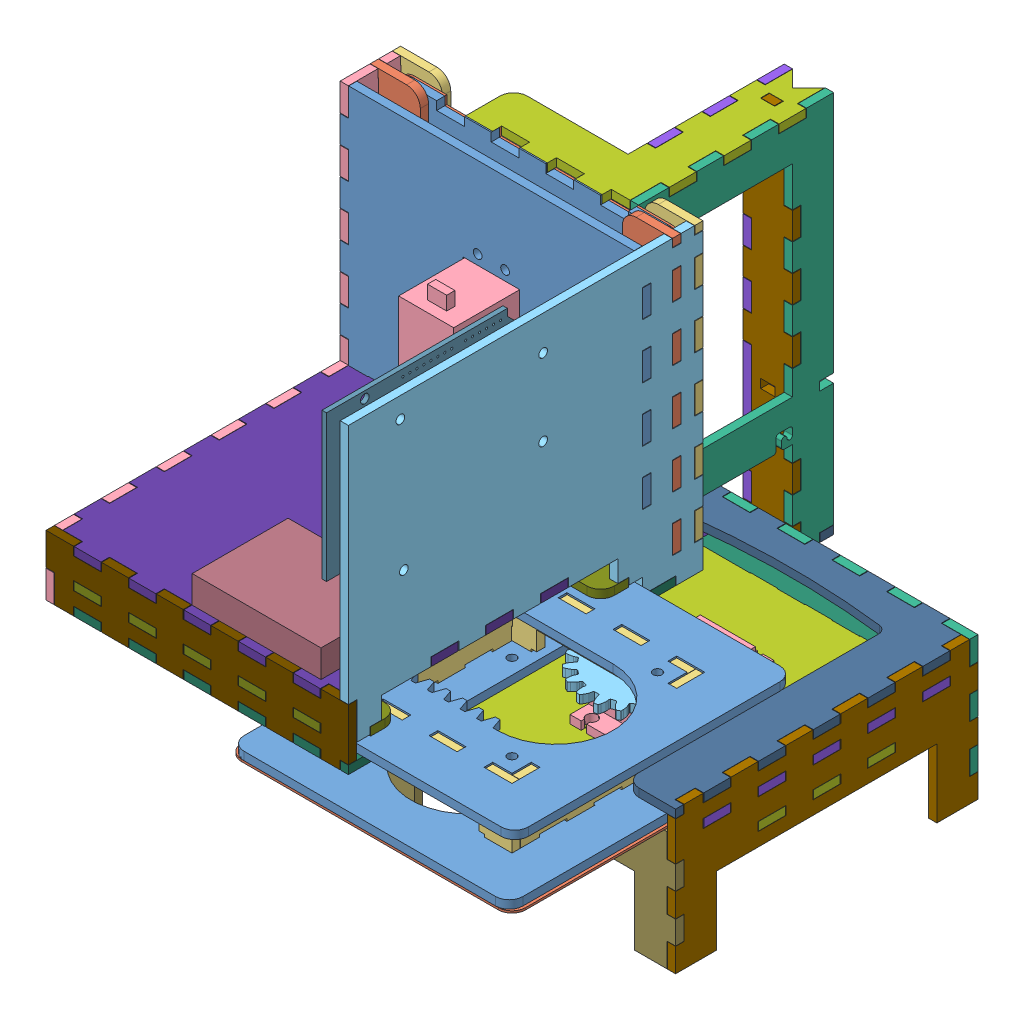
SolidWorks assembly biccolo, configuration Default. Lengths in mm.
Overall size (170.04 173.29 197.34).
41 component instances, 29 part files, 143 mates.
Components (placement in the parent):
- biccolo_rack_panel0-1: biccolo_rack_panel0 [zrack] at (0 0 186.843) size (101.74 3 103.74) (hidden)
- biccolo_rack_panel0-2: biccolo_rack_panel0 [Default] at (0 45 186.843) size (101.74 3 103.74)
- biccolo_rack_panel0-3: biccolo_rack_panel0 [Default] at (11.9708 70 174.8722) x (0 0 1) z (1 0 0) size (101.74 3 103.74)
- biccolo_rack_bearing-1: biccolo_rack_bearing [blank] at (0 45 186.843) size (103.74 0.75 103.74)
- biccolo_rack_panel1-1: biccolo_rack_panel1 [Default] at (0 45 139.8138) x (-1 0 0) z (0 -1 0) size (70.12 3 24)
- biccolo_rack_panel1-2: biccolo_rack_panel1 [Default] at (32.0585 70 174.8722) x (0 0 -1) z (0 1 0) size (70.12 3 24)
- biccolo_rack_panel1-3: biccolo_rack_panel1 [Default] at (0 45 209.9307) x (1 0 0) z (0 -1 0) size (70.12 3 24)
- biccolo_rack_panel1-4: biccolo_rack_panel1 [Default] at (-32.0585 70 174.8722) x (0 0 1) z (0 1 0) size (70.12 3 24)
- fs5106b-1: fs5106b [Default] at (0 6.2 126.843) x (0 0 1) z (-1 0 0) size (54.3 42.8 20.1)
- biccolo_6mm_gear-1: biccolo_6mm_gear [Default] at (19.0986 45 126.843) x (-1 0 0) z (0 1 0) size (41.67 41.67 3)
- biccolo_stage0_panel5-1: biccolo_stage0_panel5 [Default] at (0 0 60) x (1 0 0) z (0 -1 0) size (110.34 3 52.05)
- biccolo_stage0_panel0-1: biccolo_stage0_panel0 [Default] at (0 30 126.843) size (110.34 3 110.34)
- biccolo_stage0_panel1-1: biccolo_stage0_panel1 [Default] at (0 40.95 126.843) size (110.34 3 110.34)
- biccolo_stage0_panel3-1: biccolo_stage0_panel3 [Default] at (55.1722 0 60) x (0 0 1) z (0 -1 0) size (110.34 3 52.05)
- biccolo_stage0_panel2-1: biccolo_stage0_panel2 [Default] at (0 49.05 126.843) size (110.34 3 110.34)
- biccolo_stage0_panel4-1: biccolo_stage0_panel4 [Default] at (-55.1722 0 60) x (0 0 1) z (0 -1 0) size (110.34 3 52.05)
- biccolo_stage0_panel6-1: biccolo_stage0_panel6 [Default] at (0 0 170.3444) x (1 0 0) z (0 -1 0) size (110.34 3 43.35)
- mini_breadboard-1: mini_breadboard [Default] at (-41.0278 85 209.5444) size (47 10 35)
- biccolo_6mm_gear-3: biccolo_6mm_gear [Default] at (-40.6014 129.793 107.7) x (-1 0 0) z (0 0 -1) size (41.67 41.67 3)
- fs5106b-3: fs5106b [Default] at (-59.7 129.793 146.5) x (0 1 0) z (-1 0 0) size (54.3 42.8 20.1)
- unoboard-1: unoboard [Default] at (-19.1778 168.2944 225.0444) x (0 1 0) z (0 0 1) size (53.34 1.65 68.58)
- biccolo_6mm_gear-2: biccolo_6mm_gear [Default] at (-48.0292 70 193.9708) x (0 0 -1) z (0 -1 0) size (41.67 41.67 3)
- fs5106b-2: fs5106b [Default] at (-48.0292 108.8 174.8722) x (-1 0 0) z (0 0 1) size (54.3 42.8 20.1)
- biccolo_stage1_panel0-2: biccolo_stage1_panel0 [Default] at (-48.0292 65.95 174.8722) x (0 0 1) z (-1 0 0) size (129.39 3 110.34)
- biccolo_stage1_panel1-2: biccolo_stage1_panel1 [Default] at (-48.0292 71.05 174.8722) x (0 0 1) z (-1 0 0) size (110.34 3 110.34)
- biccolo_stage1_panel2-1: biccolo_stage1_panel2 [Default] at (-48.0292 82 174.8722) x (0 0 1) z (-1 0 0) size (110.34 3 110.34)
- biccolo_stage1_panel3-2: biccolo_stage1_panel3 [Default] at (-59.7 129.793 230.0444) x (1 0 0) z (0 -1 0) size (110.34 3 22.05)
- biccolo_stage1_panel4-2: biccolo_stage1_panel4 [Default] at (-59.7 129.793 119.7) x (1 0 0) z (0 -1 0) size (110.34 3 110.34)
- biccolo_stage1_panel5-2: biccolo_stage1_panel5 [Default] at (-59.7 129.793 111.75) x (1 0 0) z (0 -1 0) size (110.34 3 110.34)
- biccolo_stage1_panel6-1: biccolo_stage1_panel6 [Default] at (-59.7 129.793 103.65) x (1 0 0) z (0 -1 0) size (110.34 3 110.34)
- biccolo_stage1_panel7-1: biccolo_stage1_panel7 [Default] at (-114.8722 62.95 100.65) x (0 0 1) z (0 -1 0) size (129.39 3 110.34)
- biccolo_stage1_panel8-1: biccolo_stage1_panel8 [Default] at (-4.5278 62.95 100.65) x (0 0 -1) z (0 -1 0) size (129.39 3 110.34)
- biccolo_rack_panel0-4: biccolo_rack_panel0 [zrack] at (-59.7 129.793 107.7) x (1 0 0) z (0 1 0) size (101.74 3 103.74)
- biccolo_stage2_panel0-1: biccolo_stage2_panel0 [Default] at (-59.7 65.95 104.7) x (1 0 0) z (0 -1 0) size (3 74.4 139.69)
- biccolo_stage2_panel1-1: biccolo_stage2_panel1 [Default] at (-59.7 169.6944 107.7) size (69.74 3 74.3)
- biccolo_stage2_panel2-1: biccolo_stage2_panel2 [Default] at (-42.8278 169.6944 32.7) x (0 0 1) z (0 -1 0) size (74.4 3 139.69)
- biccolo_stage2_panel3-1: biccolo_stage2_panel3 [Default] at (-33.8278 169.6944 47.7) x (1 0 0) z (0 -1 0) size (18 3 139.69)
- biccolo_stage2_panel4-1: biccolo_stage2_panel4 [Default] at (-33.8278 30 47.7) size (18 3 15)
- biccolo_stage2_panel5-1: biccolo_stage2_panel5 [Default] at (-59.7 82.95 107.7) size (69.74 3 74.3)
- biccolo_rack_bearing-2: biccolo_rack_bearing [blank] at (-59.7 129.793 108.45) x (-1 0 0) z (0 1 0) size (103.74 0.75 103.74) (hidden)
- biccolo_rack_bearing-3: biccolo_rack_bearing [zrack] at (-59.7 129.793 103.95) x (1 0 0) z (0 1 0) size (103.74 0.75 103.74)
Mates (geometry in assembly coordinates):
- Coincident1: coincident anti-aligned: plane of biccolo_6mm_gear-1; plane of assembly through (0 0 0) normal (1 0 0)
- Coincident10: coincident aligned: plane of biccolo_6mm_gear-1 through (19.0986 45 126.843) normal (0 1 0); plane of assembly through (0 45 0) normal (0 1 0)
- Coincident4: coincident: unknown of biccolo_6mm_gear-1
- Coincident5: coincident aligned: plane of biccolo_rack_panel0-1 through (0 0 186.843) normal (0 1 0); plane of assembly through (0 0 0) normal (0 1 0)
- Coincident6: coincident aligned: plane of biccolo_rack_panel0-1 through (0 0 186.843) normal (1 0 0); plane of assembly through (0 0 0) normal (1 0 0)
- Coincident7: coincident: plane of biccolo_rack_panel0-1 through (0 0 186.843) normal (0 0 1)
- Coincident8: coincident aligned: circle of biccolo_6mm_gear-1; circle of fs5106b-1
- Coincident9: coincident anti-aligned: plane of fs5106b-1 through (0 6.2 126.843) normal (-1 0 0); plane of assembly through (0 0 0) normal (1 0 0)
- Coincident11: coincident aligned: plane of ? through (0 45 186.843) normal (0 1 0); plane of assembly through (0 45 0) normal (0 1 0)
- Coincident12: coincident aligned: plane of ? through (0 45 186.843) normal (1 0 0); plane of assembly through (0 0 0) normal (1 0 0)
- Distance2: distance = 60 mm aligned: unknown of biccolo_6mm_gear-1; plane of ? through (0 45 186.843) normal (0 0 1)
- Coincident15: coincident anti-aligned: unknown of biccolo_rack_panel0-3; plane of assembly through (0 70 0) normal (0 1 0)
- Concentric2: concentric anti-aligned: circle of ?; circle of biccolo_rack_panel0-3
- Concentric3: concentric anti-aligned: circle of ?; circle of biccolo_rack_panel0-3
- Coincident18: coincident anti-aligned: plane of biccolo_6mm_gear-2 through (-48.0292 70 193.9708) normal (0 -1 0); plane of assembly through (0 70 0) normal (0 1 0)
- Coincident19: coincident anti-aligned: unknown of biccolo_rack_panel0-3; unknown of biccolo_6mm_gear-2
- Distance3: distance = 60 mm aligned: unknown of biccolo_6mm_gear-2; plane of biccolo_rack_panel0-3 through (11.9708 70 174.8722) normal (1 0 0)
- Coincident21: coincident aligned: circle of biccolo_6mm_gear-2; circle of fs5106b-2
- Coincident22: coincident anti-aligned: unknown of biccolo_6mm_gear-2; plane of fs5106b-2 through (-48.0292 108.8 174.8722) normal (0 0 1)
- Coincident23: coincident aligned: plane of biccolo_stage0_panel5-1 through (0 0 60) normal (0 0 1); plane of assembly through (0 0 60) normal (0 0 1)
- Coincident24: coincident aligned: unknown of biccolo_stage0_panel5-1; plane of assembly through (0 0 0) normal (1 0 0)
- Coincident25: coincident aligned: line of biccolo_stage0_panel5-1 through (-55.1722 0 60) axis (1 0 0)
- Coincident26: coincident: plane of biccolo_stage0_panel0-1 through (0 30 126.843) normal (0 1 0)
- Parallel1: parallel aligned: plane of biccolo_stage0_panel0-1 through (0 30 126.843) normal (0 1 0); plane of assembly through (0 0 0) normal (0 1 0)
- Concentric4: concentric aligned: circle of biccolo_6mm_gear-1; circle of biccolo_stage0_panel0-1
- Coincident28: coincident aligned: plane of biccolo_stage0_panel0-1 through (0 30 126.843) normal (1 0 0); plane of assembly through (0 0 0) normal (1 0 0)
- Coincident29: coincident: plane of biccolo_stage0_panel1-1 through (0 40.95 126.843) normal (0 1 0)
- Parallel2: parallel aligned: plane of biccolo_stage0_panel1-1 through (0 40.95 126.843) normal (0 1 0); plane of assembly through (0 0 0) normal (0 1 0)
- Coincident31: coincident aligned: plane of biccolo_stage0_panel1-1 through (0 40.95 126.843) normal (1 0 0); plane of assembly through (0 0 0) normal (1 0 0)
- Concentric5: concentric aligned: circle of biccolo_6mm_gear-1; circle of biccolo_stage0_panel1-1
- Coincident32: coincident: plane of biccolo_stage0_panel2-1 through (0 49.05 126.843) normal (0 1 0)
- Parallel3: parallel aligned: plane of biccolo_stage0_panel2-1 through (0 49.05 126.843) normal (0 1 0); plane of assembly through (0 0 0) normal (0 1 0)
- Coincident34: coincident aligned: plane of biccolo_stage0_panel2-1 through (0 49.05 126.843) normal (1 0 0); plane of assembly through (0 0 0) normal (1 0 0)
- Concentric6: concentric aligned: circle of biccolo_6mm_gear-1; circle of biccolo_stage0_panel2-1
- Coincident35: coincident: line of biccolo_stage1_panel0-2 through (65.95 174.8722 0) axis (1 0 0)
- Parallel4: parallel aligned: line of biccolo_stage1_panel0-2 through (65.95 174.8722 0) axis (1 0 0); plane of assembly through (0 0 0) normal (0 1 0)
- Coincident37: coincident anti-aligned: unknown of biccolo_6mm_gear-2; plane of biccolo_stage1_panel0-2 through (-48.0292 65.95 174.8722) normal (0 0 1)
- Concentric7: concentric anti-aligned: circle of biccolo_rack_panel0-3; circle of biccolo_stage1_panel0-2
- Coincident39: coincident anti-aligned: plane of biccolo_stage1_panel0-2 through (-48.0292 65.95 107.7) normal (0 0 1); plane of biccolo_rack_panel0-4 through (-59.7 129.793 107.7) normal (0 0 -1)
- Coincident40: coincident: line of biccolo_stage1_panel0-2 through (-59.7 65.95 104.7) axis (0 0 1); unknown of biccolo_rack_panel0-4
- Parallel5: parallel aligned: unknown of biccolo_rack_panel0-4; plane of assembly through (0 0 0) normal (1 0 0)
- Coincident44: coincident: plane of biccolo_rack_panel0-4 through (-59.7 65.95 107.7) normal (0 1 0)
- Coincident45: coincident anti-aligned: plane of biccolo_stage1_panel0-2 through (-48.0292 65.95 107.7) normal (0 0 1); plane of biccolo_6mm_gear-3 through (-40.6014 129.793 107.7) normal (0 0 -1)
- Coincident46: coincident: line of biccolo_stage1_panel0-2 through (-59.7 65.95 104.7) axis (0 0 1); plane of biccolo_6mm_gear-3 through (-59.7 129.793 107.7) normal (-1 0 0)
- Parallel6: parallel anti-aligned: plane of biccolo_6mm_gear-3 through (-59.7 129.793 107.7) normal (-1 0 0); plane of assembly through (0 0 0) normal (1 0 0)
- Distance4: distance = 63.843 mm aligned: unknown of biccolo_6mm_gear-3; line of biccolo_stage1_panel0-2 through (65.95 174.8722 0) axis (1 0 0)
- Coincident50: coincident aligned: circle of biccolo_6mm_gear-3; circle of fs5106b-3
- Coincident51: coincident aligned: plane of biccolo_6mm_gear-3 through (-59.7 129.793 107.7) normal (-1 0 0); plane of fs5106b-3 through (-59.7 129.793 146.5) normal (-1 0 0)
- Coincident52: coincident: unknown of biccolo_stage1_panel1-2
- Parallel7: parallel aligned: unknown of biccolo_stage1_panel1-2; plane of assembly through (0 0 0) normal (0 1 0)
- Coincident54: coincident anti-aligned: unknown of biccolo_6mm_gear-2; plane of biccolo_stage1_panel1-2 through (-48.0292 71.05 174.8722) normal (0 0 1)
- Concentric8: concentric anti-aligned: circle of biccolo_rack_panel0-3; circle of biccolo_stage1_panel1-2
- Coincident55: coincident: unknown of biccolo_stage1_panel2-1
- Parallel8: parallel aligned: unknown of biccolo_stage1_panel2-1; plane of assembly through (0 0 0) normal (0 1 0)
- Coincident57: coincident anti-aligned: unknown of biccolo_6mm_gear-2; plane of biccolo_stage1_panel2-1 through (-48.0292 82 174.8722) normal (0 0 1)
- Concentric9: concentric anti-aligned: circle of biccolo_rack_panel0-3; circle of biccolo_stage1_panel2-1
- Coincident60: coincident: unknown of biccolo_stage1_panel0-2; plane of biccolo_stage1_panel4-2 through (-59.7 129.793 119.7) normal (0 0 1)
- Parallel9: parallel aligned: plane of biccolo_stage1_panel4-2 through (-59.7 129.793 119.7) normal (0 0 1); plane of assembly through (0 0 0) normal (0 0 1)
- Coincident62: coincident anti-aligned: plane of fs5106b-3 through (-59.7 129.793 146.5) normal (-1 0 0); unknown of biccolo_stage1_panel4-2
- Concentric10: concentric anti-aligned: circle of biccolo_rack_panel0-4; circle of biccolo_stage1_panel4-2
- Coincident63: coincident: unknown of biccolo_stage1_panel0-2; plane of biccolo_stage1_panel5-2 through (-59.7 129.793 111.75) normal (0 0 1)
- Parallel10: parallel aligned: plane of biccolo_stage1_panel5-2 through (-59.7 129.793 111.75) normal (0 0 1); plane of assembly through (0 0 0) normal (0 0 1)
- Concentric11: concentric anti-aligned: circle of biccolo_6mm_gear-3; circle of biccolo_stage1_panel5-2
- Coincident66: coincident aligned: unknown of biccolo_stage1_panel4-2; unknown of biccolo_stage1_panel5-2
- Coincident67: coincident: unknown of biccolo_stage1_panel0-2; plane of biccolo_stage1_panel6-1 through (-59.7 129.793 103.65) normal (0 0 1)
- Parallel12: parallel aligned: plane of biccolo_stage1_panel6-1 through (-59.7 129.793 103.65) normal (0 0 1); plane of assembly through (0 0 0) normal (0 0 1)
- Coincident70: coincident aligned: unknown of biccolo_stage1_panel4-2; unknown of biccolo_stage1_panel6-1
- Concentric12: concentric anti-aligned: circle of biccolo_6mm_gear-3; circle of biccolo_stage1_panel6-1
- Coincident71: coincident: unknown of biccolo_stage1_panel0-2; plane of biccolo_stage1_panel3-2 through (-59.7 129.793 230.0444) normal (0 0 1)
- Parallel13: parallel aligned: plane of biccolo_stage1_panel3-2 through (-59.7 129.793 230.0444) normal (0 0 1); plane of assembly through (0 0 0) normal (0 0 1)
- Coincident73: coincident aligned: unknown of biccolo_stage1_panel4-2; unknown of biccolo_stage1_panel3-2
- Concentric13: concentric anti-aligned: circle of biccolo_6mm_gear-3; circle of biccolo_stage1_panel3-2
- Coincident74: coincident: unknown of biccolo_stage1_panel0-2; unknown of biccolo_stage1_panel7-1
- Parallel14: parallel anti-aligned: unknown of biccolo_stage1_panel7-1; plane of assembly through (0 0 0) normal (1 0 0)
- Coincident76: coincident: unknown of biccolo_stage1_panel4-2; plane of biccolo_stage1_panel7-1 through (-114.8722 62.95 100.65) normal (0 -1 0)
- Parallel15: parallel anti-aligned: plane of biccolo_stage1_panel7-1 through (-114.8722 62.95 100.65) normal (0 -1 0); plane of assembly through (0 0 0) normal (0 1 0)
- Coincident78: coincident: line of biccolo_stage1_panel0-2 through (-4.5278 65.95 100.65) axis (-1 0 0); unknown of biccolo_stage1_panel7-1
- Coincident79: coincident: unknown of biccolo_stage1_panel0-2; unknown of biccolo_stage1_panel8-1
- Parallel16: parallel aligned: unknown of biccolo_stage1_panel8-1; plane of assembly through (0 0 0) normal (1 0 0)
- Coincident81: coincident: plane of biccolo_stage1_panel8-1 through (-4.5278 62.95 100.65) normal (0 -1 0)
- Coincident82: coincident: unknown of biccolo_stage1_panel0-2; line of biccolo_stage1_panel8-1 through (-4.5278 62.95 100.65) axis (0 1 0)
- Distance5: distance = 10 mm anti-aligned: plane of unoboard-1 through (-17.5278 168.2944 225.0444) normal (1 0 0); plane of biccolo_stage1_panel8-1 through (-7.5278 62.95 100.65) normal (-1 0 0)
- Distance6: distance = 5 mm aligned: plane of unoboard-1 through (-17.5278 168.2944 225.0444) normal (0 1 0); plane of biccolo_stage1_panel8-1 through (-7.5278 173.2944 100.65) normal (0 1 0)
- Distance7: distance = 5 mm aligned: plane of biccolo_stage1_panel8-1 through (-7.5278 71.05 230.0444) normal (0 0 1); plane of unoboard-1 through (-17.5278 168.2944 225.0444) normal (0 0 1)
- Coincident86: coincident aligned: unknown of biccolo_rack_panel0-4; unknown of biccolo_stage2_panel0-1
- Coincident87: coincident anti-aligned: plane of biccolo_rack_panel0-4 through (-59.7 133.636 104.7) normal (0 0 -1); plane of biccolo_stage2_panel0-1 through (-59.7 65.95 104.7) normal (0 0 1)
- Coincident88: coincident anti-aligned: plane of biccolo_rack_panel0-4 through (-59.7 65.95 107.7) normal (0 1 0); plane of biccolo_stage2_panel0-1 through (-59.7 65.95 104.7) normal (0 -1 0)
- Coincident89: coincident: unknown of biccolo_stage2_panel0-1; plane of biccolo_stage2_panel1-1 through (-59.7 169.6944 107.7) normal (0 1 0)
- Coincident91: coincident aligned: unknown of biccolo_stage2_panel0-1; plane of biccolo_stage2_panel1-1 through (-59.7 169.6944 107.7) normal (1 0 0)
- Parallel17: parallel aligned: plane of biccolo_stage2_panel1-1 through (-59.7 169.6944 107.7) normal (0 1 0); plane of assembly through (0 0 0) normal (0 1 0)
- Coincident93: coincident anti-aligned: plane of biccolo_rack_panel0-4 through (-59.7 129.793 107.7) normal (0 0 -1); plane of biccolo_stage2_panel1-1 through (-59.7 169.6944 107.7) normal (0 0 1)
- Coincident94: coincident: line of biccolo_stage2_panel1-1 through (-42.8278 169.6944 32.7) axis (0 0 1); unknown of biccolo_stage2_panel2-1
- Coincident95: coincident: line of biccolo_stage2_panel1-1 through (-94.5722 169.6944 32.7) axis (1 0 0); unknown of biccolo_stage2_panel2-1
- Parallel18: parallel anti-aligned: plane of biccolo_stage2_panel2-1 through (-42.8278 169.6944 32.7) normal (0 -1 0); plane of assembly through (0 0 0) normal (0 1 0)
- Coincident98: coincident: unknown of biccolo_stage2_panel1-1; plane of biccolo_stage2_panel2-1 through (-42.8278 169.6944 32.7) normal (0 -1 0)
- Coincident99: coincident: unknown of biccolo_stage2_panel1-1; plane of biccolo_stage2_panel3-1 through (-33.8278 169.6944 47.7) normal (0 0 1)
- Parallel19: parallel anti-aligned: plane of biccolo_stage2_panel3-1 through (-33.8278 169.6944 47.7) normal (0 -1 0); plane of assembly through (0 0 0) normal (0 1 0)
- Coincident101: coincident: line of biccolo_stage2_panel1-1 through (-33.8278 169.6944 32.7) axis (0 0 1); unknown of biccolo_stage2_panel3-1
- Coincident102: coincident: unknown of biccolo_stage2_panel1-1; plane of biccolo_stage2_panel3-1 through (-33.8278 169.6944 47.7) normal (0 -1 0)
- Coincident103: coincident aligned: unknown of biccolo_stage0_panel3-1; plane of assembly through (0 0 60) normal (0 0 1)
- Coincident104: coincident anti-aligned: plane of biccolo_stage0_panel3-1 through (55.1722 0 60) normal (0 -1 0); plane of assembly through (0 0 0) normal (0 1 0)
- Coincident105: coincident: unknown of biccolo_stage0_panel5-1; unknown of biccolo_stage0_panel3-1
- Coincident106: coincident: unknown of biccolo_stage0_panel5-1; unknown of biccolo_stage0_panel4-1
- Coincident107: coincident anti-aligned: plane of biccolo_stage0_panel4-1 through (-55.1722 0 60) normal (0 -1 0); plane of assembly through (0 0 0) normal (0 1 0)
- Coincident108: coincident aligned: unknown of biccolo_stage0_panel4-1; plane of assembly through (0 0 60) normal (0 0 1)
- Coincident109: coincident: plane of biccolo_stage0_panel6-1 through (0 0 170.3444) normal (0 0 1)
- Coincident110: coincident anti-aligned: plane of biccolo_stage0_panel6-1 through (0 0 170.3444) normal (0 -1 0); plane of assembly through (0 0 0) normal (0 1 0)
- Coincident111: coincident aligned: plane of biccolo_stage0_panel0-1 through (0 30 126.843) normal (1 0 0); unknown of biccolo_stage0_panel6-1
- Coincident112: coincident anti-aligned: plane of biccolo_stage1_panel2-1 through (-48.0292 85 174.8722) normal (0 1 0); plane of mini_breadboard-1 through (-41.0278 85 209.5444) normal (0 -1 0)
- Distance10: distance = 3 mm aligned: plane of mini_breadboard-1 through (-64.5278 95 227.0444) normal (0 0 1); plane of biccolo_stage1_panel3-2 through (-59.7 129.793 230.0444) normal (0 0 1)
- Distance11: distance = 10 mm anti-aligned: plane of biccolo_stage1_panel8-1 through (-7.5278 62.95 100.65) normal (-1 0 0); plane of mini_breadboard-1 through (-17.5278 95 192.0444) normal (1 0 0)
- Coincident117: coincident aligned: plane of ? through (0 45 186.843) normal (0 1 0); plane of ? through (0 45 186.843) normal (0 1 0)
- Coincident118: coincident aligned: plane of ? through (0 45 186.843) normal (1 0 0); plane of ? through (0 45 186.843) normal (1 0 0)
- Coincident119: coincident aligned: plane of ? through (0 45 186.843) normal (0 0 1); plane of ? through (0 45 186.843) normal (0 0 1)
- Coincident120: coincident: plane of biccolo_rack_panel1-1 through (0 45 139.8138) normal (0 -1 0)
- Coincident121: coincident: unknown of biccolo_rack_panel1-1; line of ? through (-35.0585 45 139.8138) axis (1 0 0)
- Coincident122: coincident anti-aligned: unknown of biccolo_rack_panel1-1; plane of assembly through (0 0 0) normal (1 0 0)
- Coincident123: coincident: unknown of biccolo_rack_panel1-2; line of ? through (32.0585 45 206.9307) axis (0 0 -1)
- Coincident124: coincident: unknown of biccolo_rack_panel1-2; line of ? through (-51.8722 45 174.8722) axis (1 0 0)
- Coincident125: coincident: plane of biccolo_rack_panel1-2 through (32.0585 70 174.8722) normal (0 1 0)
- Parallel20: parallel anti-aligned: unknown of biccolo_rack_panel1-2; plane of assembly through (0 0 0) normal (1 0 0)
- Coincident127: coincident: plane of biccolo_rack_panel1-3 through (0 45 209.9307) normal (0 0 1); line of ? through (-35.0585 45 209.9307) axis (1 0 0)
- Parallel21: parallel aligned: plane of biccolo_rack_panel1-3 through (0 45 209.9307) normal (0 0 1); plane of assembly through (0 0 0) normal (0 0 1)
- Coincident129: coincident aligned: unknown of biccolo_rack_panel1-3; plane of assembly through (0 0 0) normal (1 0 0)
- Coincident130: coincident: plane of biccolo_rack_panel1-3 through (0 45 209.9307) normal (0 -1 0)
- Coincident131: coincident: unknown of biccolo_rack_panel1-4; line of ? through (-32.0585 45 206.9307) axis (0 0 -1)
- Parallel22: parallel aligned: unknown of biccolo_rack_panel1-4; plane of assembly through (0 0 0) normal (1 0 0)
- Coincident133: coincident: line of ? through (-51.8722 45 174.8722) axis (1 0 0); unknown of biccolo_rack_panel1-4
- Coincident134: coincident: plane of biccolo_rack_panel1-4 through (-32.0585 70 174.8722) normal (0 1 0)
- Parallel23: parallel anti-aligned: plane of biccolo_rack_panel0-4 through (-59.7 129.793 107.7) normal (0 0 -1); unknown of biccolo_rack_bearing-2
- Coincident136: coincident: line of biccolo_stage2_panel0-1 through (-59.7 65.95 104.7) axis (0 1 0); unknown of biccolo_rack_bearing-2
- Coincident137: coincident: line of biccolo_stage2_panel1-1 through (-94.5722 169.6944 108.45) axis (1 0 0); unknown of biccolo_rack_bearing-2
- Parallel24: parallel aligned: plane of biccolo_rack_panel0-4 through (-59.7 129.793 107.7) normal (0 0 -1); plane of biccolo_rack_bearing-3 through (-59.7 129.793 103.95) normal (0 0 -1)
- Coincident143: coincident aligned: plane of biccolo_stage2_panel3-1 through (-33.8278 169.6944 47.7) normal (0 0 1); plane of biccolo_stage2_panel4-1 through (-33.8278 30 47.7) normal (0 0 1)
- Coincident144: coincident aligned: unknown of biccolo_stage2_panel3-1; plane of biccolo_stage2_panel4-1 through (-33.8278 30 47.7) normal (1 0 0)
- Coincident145: coincident: line of biccolo_stage2_panel3-1 through (-42.8278 30 47.7) axis (1 0 0); plane of biccolo_stage2_panel4-1 through (-33.8278 30 47.7) normal (0 1 0)
- Coincident149: coincident: unknown of biccolo_stage2_panel1-1; plane of biccolo_rack_bearing-3 through (-59.7 129.793 103.95) normal (0 0 -1)
- Coincident150: coincident aligned: unknown of biccolo_rack_panel0-4; unknown of biccolo_rack_bearing-3
- Concentric16: concentric aligned: circle of biccolo_rack_panel0-4; circle of biccolo_rack_bearing-3
- Coincident151: coincident aligned: unknown of biccolo_rack_panel0-4; plane of biccolo_stage2_panel5-1 through (-59.7 82.95 107.7) normal (1 0 0)
- Coincident152: coincident anti-aligned: plane of biccolo_rack_panel0-4 through (-59.7 129.793 107.7) normal (0 0 -1); plane of biccolo_stage2_panel5-1 through (-59.7 82.95 107.7) normal (0 0 1)
- Coincident153: coincident: line of biccolo_rack_panel0-4 through (-7.8278 82.95 107.7) axis (-1 0 0); plane of biccolo_stage2_panel5-1 through (-59.7 82.95 107.7) normal (0 1 0)
- Concentric17: concentric anti-aligned: circle of biccolo_rack_panel0-4; circle of biccolo_rack_bearing-2
